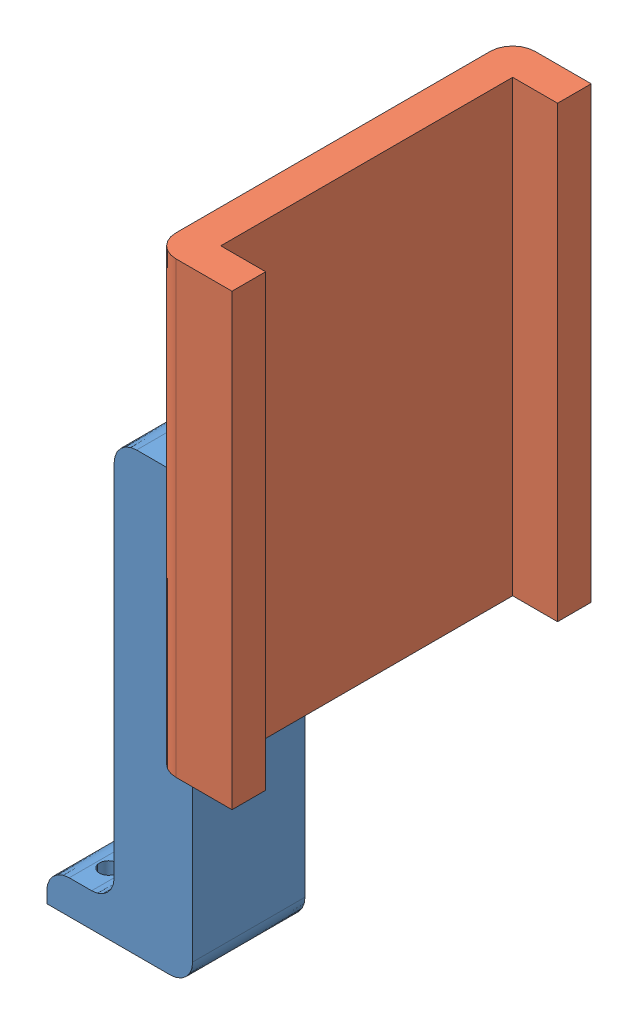
SolidWorks assembly npx_holder_with_leg, configuration Default. Lengths in mm.
Overall size (6.25 16 8).
2 component instances, 2 part files, 4 mates.
Components (placement in the parent):
- littlel-1: littlel [Default] at (3.5539 4.8106 4.4198) size (4.5 9.75 2.5)
- npx_holder_shaft-1: npx_holder_shaft [Default] at (5.0896 8.0606 4.4198) x (0 0 -1) z (1 0 0) size (8 10 1.75)
Mates (geometry in assembly coordinates):
- Coincident1: coincident: plane of assembly through (0 0 0) normal (0 0 1); plane of littlel-1 through (3.5539 4.8106 4.4198) normal (0 0 1); plane of assembly
- Coincident3: coincident anti-aligned: plane of littlel-1 through (5.0896 4.8106 3.7948) normal (1 0 0); plane of npx_holder_shaft-1 through (5.0896 8.0606 4.4198) normal (-1 0 0)
- Coincident4: coincident anti-aligned: plane of littlel-1 through (3.5539 4.8106 4.4198) normal (0 0 1); plane of npx_holder_shaft-1 through (5.0896 8.0606 4.4198) normal (0 0 -1)
- Distance1: distance = 2 mm: line of littlel-1 through (2.0896 5.0606 4.4198) axis (1 0 0); plane of npx_holder_shaft-1 through (5.8396 3.0606 4.4198) normal (0 -1 0)
